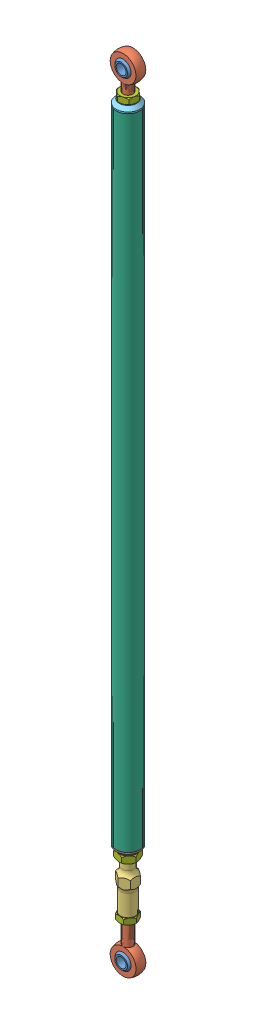
SolidWorks assembly PushRodF, configuration Default. Lengths in mm.
Overall size (111.88 645.93 26.73).
13 component instances, 7 part files, 16 mates.
Components (placement in the parent):
- RodEnd312Male-4: RodEnd312Male [Default] at (0 21.6726 0) x (0.999999 0 0.001394) z (-0.001394 0 0.999999) size (22.23 58.75 22.2)
  - RodEndBall312-1: RodEndBall312 [Default] at origin size (15.06 15.06 22.2)
  - RodEndRace312Male-1: RodEndRace312Male [Default] at origin size (22.23 58.75 7.94)
- RodEnd312Male-2: RodEnd312Male [Default] at (0 -602.0274 0) x (0.999997 0 -0.002301) z (-0.002301 0 -0.999997) size (22.23 58.75 22.2)
  - RodEndBall312-1: RodEndBall312 [Default] at origin size (15.06 15.06 22.2)
  - RodEndRace312Male-1: RodEndRace312Male [Default] at origin size (22.23 58.75 7.94)
- RodEndAdjuster312-2: RodEndAdjuster312 [Default] at (0 -543.3274 0) x (0.996855 0 0.079253) z (-0.079253 0 0.996855) size (13 57.4 16.97)
- ControlArmEnd75-375-2: ControlArmEnd75-375 [Default] at (0 -525.3274 0) x (0.613987 0 0.789316) z (-0.789316 0 0.613987) size (19.05 7 19.05)
- ControlArmEnd75-312-1: ControlArmEnd75-312 [Default] at (0 -1.3274 0) x (-0.829588 0 -0.558376) z (-0.558376 0 0.829588) size (19.05 7 19.05)
- PushRodTubeF-1: PushRodTubeF [No Fairing] at origin size (111.88 516 22.33)
- Hex Jam Nut_AI-1: Hex Jam Nut_AI [HJNUT 0.3125-24-D-N] at (0 -1.3274 0) x (0.979645 0 0.200739) z (0 -1 0) size (12.7 14.66 4.95)
- Hex Jam Nut_AI-2: Hex Jam Nut_AI [HJNUT 0.3125-24-D-N] at (0 -569.3274 0) x (-0.078515 0 0.996913) z (0 1 0) size (12.7 14.66 4.95)
- Hex Jam Nut_AI-3: Hex Jam Nut_AI [HJNUT 0.375-24-D-N] at (0 -531.0932 0) x (-0.75236 0 -0.658752) z (0 -1 0) size (14.27 16.48 5.77)
Mates (geometry in assembly coordinates):
- Concentric7: concentric: cylinder of assembly; cylinder of assembly; cylinder of ControlArmEnd75-375-2 through (0 -521.3274 0) axis (0 1 0) radius 7.925; cylinder of PushRodTubeF-1 through (0 -5.3274 0) axis (0 -1 0) radius 8.325
- Coincident17: coincident: plane of assembly; plane of assembly; plane of ControlArmEnd75-375-2 through (0 -521.3274 0) normal (0 1 0); plane of PushRodTubeF-1 through (0 -521.3274 0) normal (0 -1 0)
- Concentric9: concentric: cylinder of ? through (0 13.5601 0) axis (0 -1 0) radius 3.9688; line of PushRodTubeF-1 through (468 0 -521.3274) axis (0 0 1)
- Coincident10: coincident: plane of assembly; plane of assembly; plane of ControlArmEnd75-312-1 through (0 -5.3274 0) normal (0 -1 0); plane of PushRodTubeF-1 through (0 -5.3274 0) normal (0 1 0)
- Concentric12: concentric: cylinder of assembly; cylinder of RodEndAdjuster312-2 through (0 -511.9274 0) axis (0 -1 0) radius 4.7625; line of PushRodTubeF-1 through (468 0 -521.3274) axis (0 0 1)
- Distance13: distance = 23 mm: plane of ? through (0 21.6726 0) normal (0 1 0); plane of ControlArmEnd75-312-1 through (0 -1.3274 0) normal (0 1 0)
- Concentric112: concentric: line of PushRodTubeF-1 through (468 0 -521.3274) axis (0 0 1); cylinder of ? through (0 -593.9149 0) axis (0 1 0) radius 3.9688
- Concentric113: concentric: cylinder of assembly; cylinder of assembly; cylinder of ControlArmEnd75-312-1 through (0 -5.3274 0) axis (0 -1 0) radius 7.925; cylinder of PushRodTubeF-1 through (0 -5.3274 0) axis (0 -1 0) radius 8.325
- Concentric114: concentric: circle of ?; circle of Hex Jam Nut_AI-1
- Coincident18: coincident: plane of assembly; plane of assembly; plane of ControlArmEnd75-312-1 through (0 -1.3274 0) normal (0 1 0); plane of Hex Jam Nut_AI-1 through (-1.4719 -1.3274 7.1831) normal (0 -1 0)
- Concentric115: concentric: cylinder of ? through (0 -593.9149 0) axis (0 1 0) radius 3.9688; unknown of Hex Jam Nut_AI-2
- Coincident19: coincident: plane of assembly; plane of assembly; plane of RodEndAdjuster312-2 through (0 -569.3274 0) normal (0 -1 0); plane of Hex Jam Nut_AI-2 through (7.3097 -569.3274 0.5757) normal (0 1 0)
- Concentric116: concentric: cylinder of assembly; cylinder of assembly; cylinder of ControlArmEnd75-375-2 through (0 -525.3274 0) axis (0 -1 0) radius 4.2164; cylinder of Hex Jam Nut_AI-3 through (0 -506.0557 0) axis (0 -1 0) radius 4.7625
- Coincident20: coincident: plane of assembly; plane of assembly; plane of ControlArmEnd75-375-2 through (0 -525.3274 0) normal (0 -1 0); plane of Hex Jam Nut_AI-3 through (10.7398 -525.3274 9.4035) normal (0 1 0)
- Distance14: distance = 623.7 mm: point of RodEnd312Male-4/RodEndBall312-1; point of RodEnd312Male-2/RodEndBall312-1
- Distance15: distance = 44 mm: plane of assembly; plane of assembly; plane of RodEndAdjuster312-2 through (0 -569.3274 0) normal (0 -1 0); plane of ControlArmEnd75-375-2 through (0 -525.3274 0) normal (0 -1 0)
